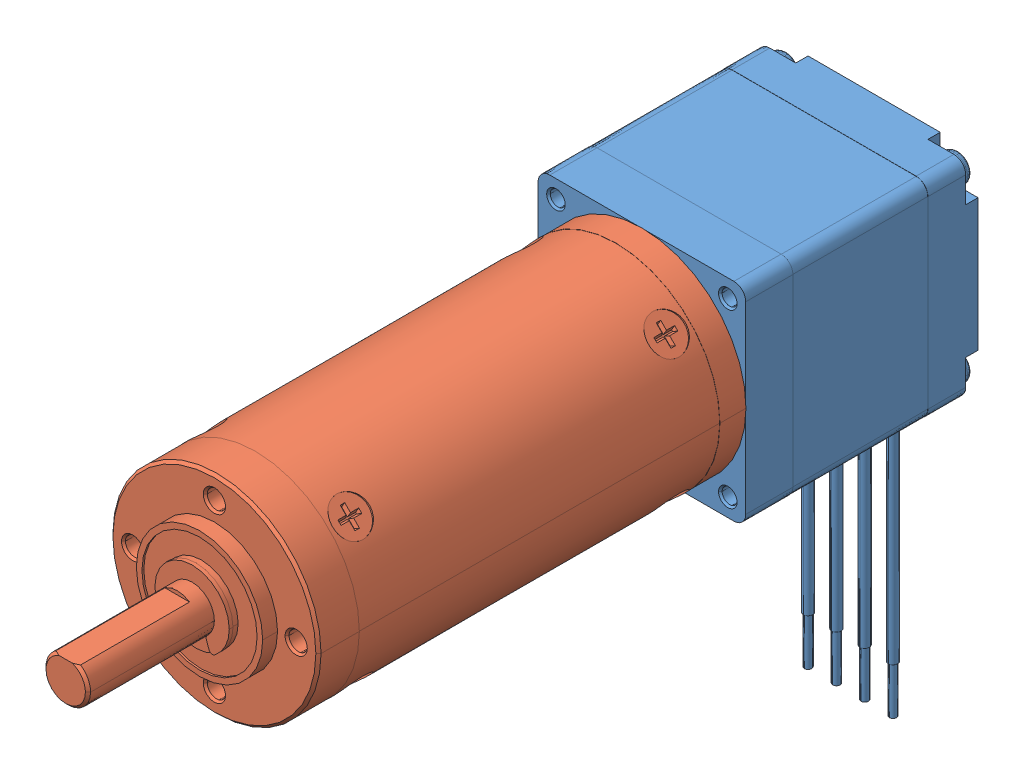
SolidWorks assembly 11YPG1-R189, configuration Default. Lengths in mm.
Overall size (28 67.98 109).
3 component instances, 2 part files, 0 mates.
Components (placement in the parent):
- 11YPG1-R189.STEP-1: 11YPG1-R189.STEP [Default] at origin size (28 67.98 109)
  - 11Y Series_11Y102S-LW4.STEP-1: 11Y Series_11Y102S-LW4.STEP [Default] at origin size (27.94 67.95 51.31)
  - 11YPG Gearbox_11YPG-R189.STEP-1: 11YPG Gearbox_11YPG-R189.STEP [Default] at (0 0 57.5) size (28 28 77.5)
